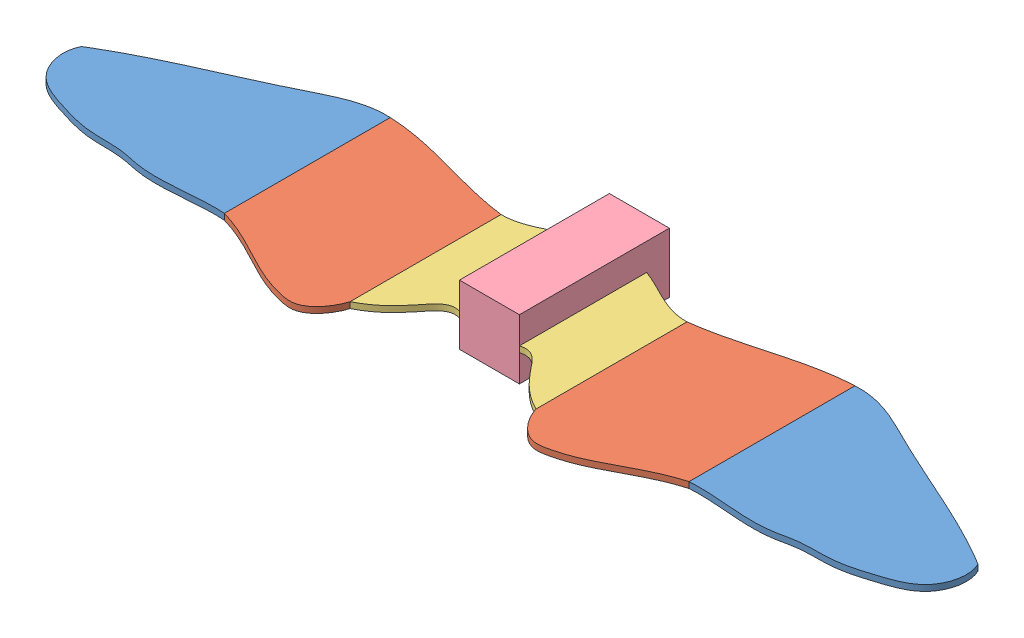
SolidWorks assembly wing_assembly, configuration Default. Lengths in mm.
Overall size (607.3 40 203.11).
7 component instances, 4 part files, 12 mates.
Components (placement in the parent):
- hand_wing-2: hand_wing [Default] at (-115.8134 -0.9709 29.1793) size (148.69 4 116.69)
- mid_wing-2: mid_wing [Default] at (-115.8134 -0.9709 29.1793) size (92.96 4 141.94)
- upper_wing-2: upper_wing [Default] at (-115.8134 -0.9709 29.1793) size (42 4 115.75)
- torso_temporary-1: torso_temporary [Default] at (164.87 -18.9709 -21.3398) size (40 40 100)
- upper_wing-3: upper_wing [Default] at (485.5535 3.0291 29.1793) x (-1 0 0) z (0 0 1) size (42 4 115.75)
- mid_wing-3: mid_wing [Default] at (485.5535 3.0291 29.1793) x (-1 0 0) z (0 0 1) size (92.96 4 141.94)
- hand_wing-3: hand_wing [Default] at (485.5535 3.0291 29.1793) x (-1 0 0) z (0 0 1) size (148.69 4 116.69)
Mates (geometry in assembly coordinates):
- Coincident1: coincident aligned: line of hand_wing-2 through (29.9094 1.0291 0.5023) axis (0 0 -1); line of mid_wing-2 through (29.9094 1.0291 0.5023) axis (0 0 -1)
- Coincident2: coincident: moEndPointRef_w of hand_wing-2; moEndPointRef_w of mid_wing-2
- Coincident3: coincident aligned: line of mid_wing-2 through (122.872 1.0291 9.5984) axis (0 0 -1); line of upper_wing-2 through (122.872 1.0291 9.5984) axis (0 0 -1)
- Coincident4: coincident: moEndPointRef_w of mid_wing-2; moEndPointRef_w of upper_wing-2
- Coincident5: coincident aligned: line of upper_wing-2 through (164.87 1.0291 -21.3398) axis (0 0 -1); line of torso_temporary-1 through (164.87 1.0291 -21.3398) axis (0 0 -1)
- Coincident6: coincident: moEndPointRef_w of upper_wing-2; moEndPointRef_w of torso_temporary-1
- Coincident8: coincident aligned: line of torso_temporary-1 through (204.87 1.0291 -21.3398) axis (0 0 -1); line of upper_wing-3 through (204.87 1.0291 -21.3398) axis (0 0 -1)
- Coincident9: coincident: moEndPointRef_w of torso_temporary-1; moEndPointRef_w of upper_wing-3
- Coincident11: coincident aligned: line of upper_wing-3 through (246.8681 1.0291 9.5984) axis (0 0 -1); line of mid_wing-3 through (246.8681 1.0291 9.5984) axis (0 0 -1)
- Coincident12: coincident: moEndPointRef_w of upper_wing-3; moEndPointRef_w of mid_wing-3
- Coincident14: coincident aligned: line of mid_wing-3 through (339.8307 1.0291 0.5023) axis (0 0 -1); line of hand_wing-3 through (339.8307 1.0291 0.5023) axis (0 0 -1)
- Coincident15: coincident: moEndPointRef_w of mid_wing-3; moEndPointRef_w of hand_wing-3
